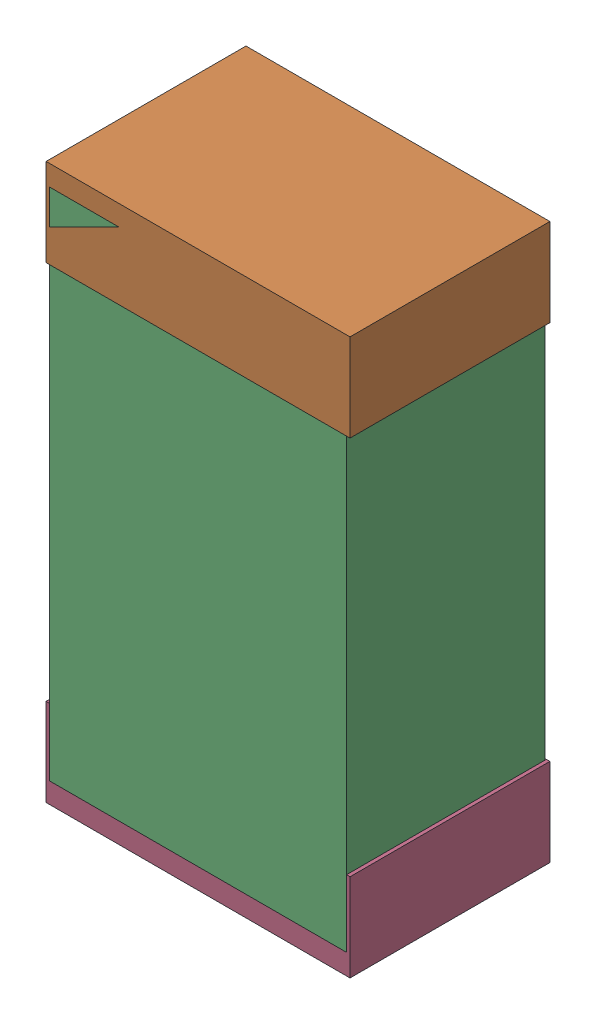
SolidWorks assembly Bat2StatKanaloa_v2.0.0_Power, configuration Default. Lengths in mm.
Overall size (1.3 2.38 0.87).
8 component instances, 3 part files, 0 mates.
Components (placement in the parent):
- 440440848-1: 440440848 [Default] at (101.65 64.675 -1.9724) size (0.51 1.02 0.87)
  - Extruded_4-1: Extruded_4 [Default] at origin size (0.51 1.02 0.87)
- 330415056-1: 330415056 [Default] at (101.65 65.675 -1.9574) size (1.3 0.38 0.85)
  - Extruded_2-1: Extruded_2 [Default] at origin size (1.3 0.38 0.85)
- 352877008-1: 352877008 [Default] at (101.65 64.675 -1.9524) size (1.27 2.2 0.85)
  - Extruded_3-1: Extruded_3 [Default] at origin size (1.27 2.2 0.85)
- 330415056-2: 330415056 [Default] at (101.65 63.675 -1.9574) size (1.3 0.38 0.85)
  - Extruded_2-1: Extruded_2 [Default] at origin size (1.3 0.38 0.85)
